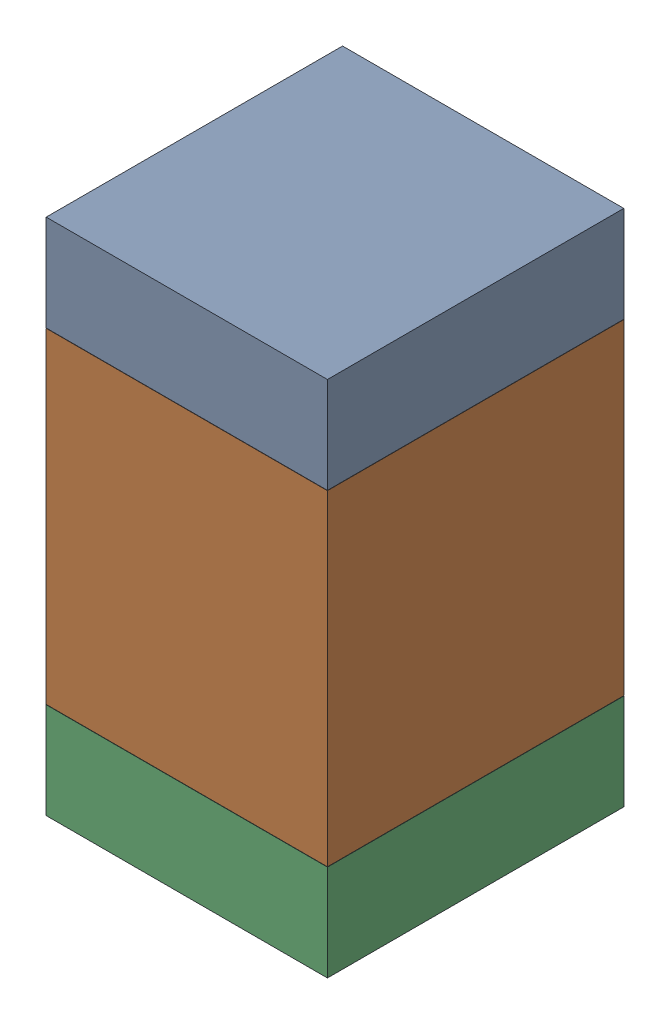
SolidWorks assembly C26, configuration Default. Lengths in mm.
Overall size (0.95 1.75 1).
6 component instances, 2 part files, 0 mates.
Components (placement in the parent):
- 6575495072-1: 6575495072 [Default] at (43.307 6.8085 0) size (0.95 0.32 1)
  - Extruded_6-1: Extruded_6 [Default] at origin size (0.95 0.32 1)
- 6575494912-1: 6575494912 [Default] at (43.307 6.096 0) size (0.95 1.1 1)
  - Extruded_7-1: Extruded_7 [Default] at origin size (0.95 1.1 1)
- 6575495072-2: 6575495072 [Default] at (43.307 5.3835 0) size (0.95 0.32 1)
  - Extruded_6-1: Extruded_6 [Default] at origin size (0.95 0.32 1)
